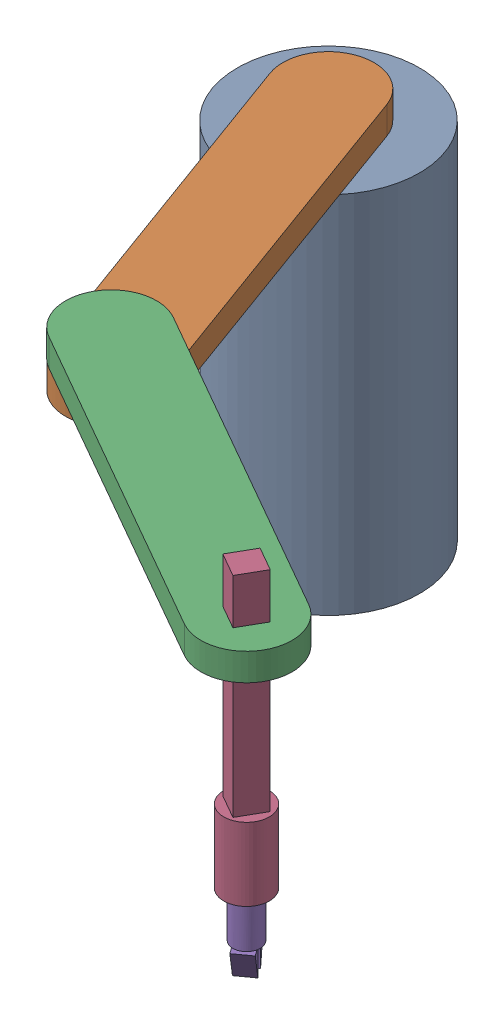
SolidWorks assembly 装配体, configuration Default. Lengths in mm.
Overall size (652.63 509.72 742.56).
5 component instances, 5 part files, 10 mates.
Components (placement in the parent):
- base-1: base [默认] at (-261.4597 0 143.5301) size (200 400 200)
- bigarm-1: bigarm [默认] at (-192.8652 400 331.3991) x (-0.939345 0 0.342973) z (-0.342973 0 -0.939345) size (100 30 500)
- forearm-1: forearm [默认] at (49.3373 430 618.5671) x (-0.496495 0 0.86804) z (-0.86804 0 -0.496495) size (100 30 500)
- hand-1: hand [默认] at (222.9453 199.7226 717.866) x (-0.496495 0 0.86804) z (-0.86804 0 -0.496495) size (50 310 50)
- finger-1: finger [默认] at (222.9453 149.7226 717.866) x (0.585997 0 0.810313) z (-0.810313 0 0.585997) size (39 80 30)
Mates (geometry in assembly coordinates):
- 同心2: concentric aligned: cylinder of base-1 through (-261.4597 400 143.5301) axis (0 -1 0) radius 100; cylinder of bigarm-1 through (-261.4597 430 143.5301) axis (0 -1 0) radius 50
- 重合2: coincident anti-aligned: plane of base-1 through (-261.4597 400 143.5301) normal (0 1 0); plane of bigarm-1 through (-124.2706 400 519.2682) normal (0 -1 0)
- 同心3: concentric aligned: cylinder of bigarm-1 through (-124.2706 430 519.2682) axis (0 -1 0) radius 50; cylinder of forearm-1 through (-124.2706 460 519.2682) axis (0 -1 0) radius 50
- 重合3: coincident anti-aligned: plane of bigarm-1 through (-124.2706 430 519.2682) normal (0 1 0); plane of forearm-1 through (222.9453 430 717.866) normal (0 -1 0)
- 重合4: coincident anti-aligned: plane of forearm-1 through (243.4133 430 712.2929) normal (-0.86804 0 -0.496495); plane of hand-1 through (243.4133 509.7226 712.2929) normal (0.86804 0 0.496495)
- 重合5: coincident anti-aligned: plane of forearm-1 through (202.4773 430 723.4392) normal (0.496495 0 -0.86804); plane of hand-1 through (228.5185 509.7226 738.3341) normal (-0.496495 0 0.86804)
- LimitDistance1: limit distance = 49.7226 mm aligned: plane of forearm-1 through (222.9453 460 717.866) normal (0 1 0); plane of hand-1 through (222.9453 509.7226 717.866) normal (0 1 0)
- 重合7: coincident anti-aligned: plane of base-1 through (-261.4597 0 143.5301) normal (0 -1 0)
- 重合8: coincident anti-aligned: plane of hand-1 through (222.9453 199.7226 717.866) normal (0 -1 0); plane of finger-1 through (222.9453 199.7226 717.866) normal (0 1 0)
- 同心4: concentric aligned: cylinder of hand-1 through (222.9453 279.7226 717.866) axis (0 -1 0) radius 25; cylinder of finger-1 through (222.9453 199.7226 717.866) axis (0 -1 0) radius 15
